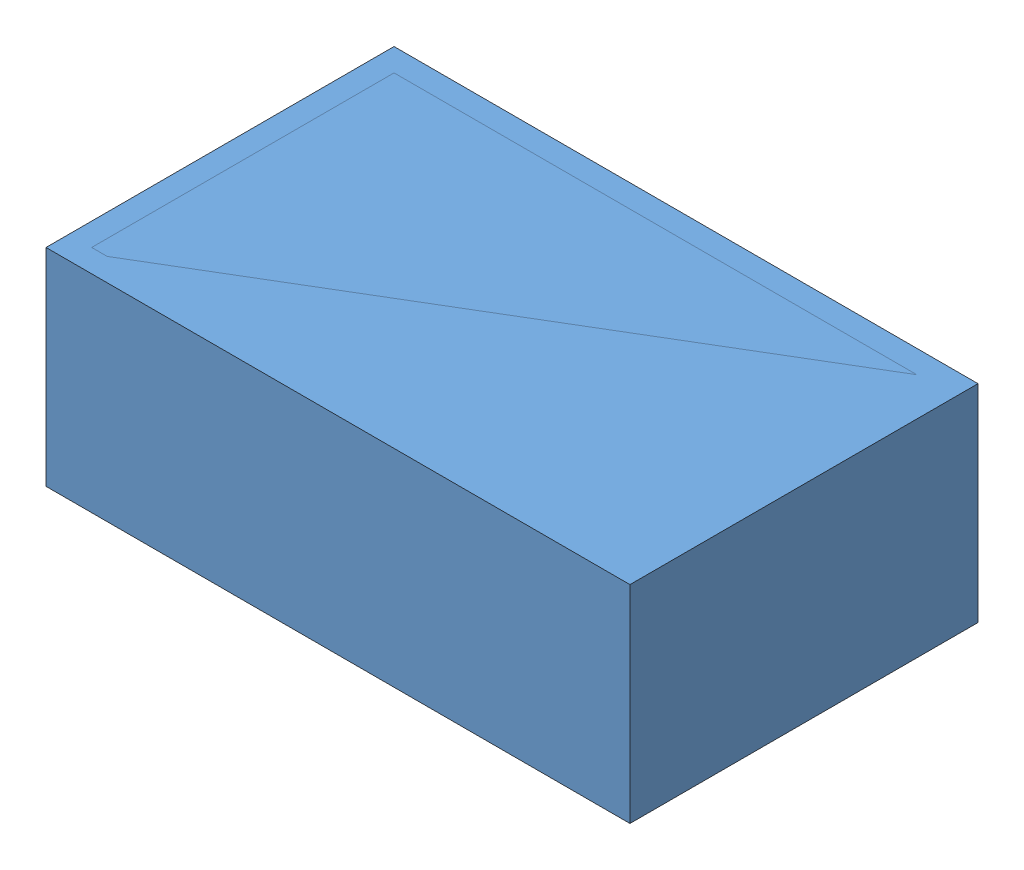
SolidWorks assembly Коробка 90х150х53 в сборе, configuration По умолчанию. Lengths in mm.
Overall size (153.02 53.98 92.02).
2 component instances, 2 part files, 4 mates.
Components (placement in the parent):
- Коробка 90х150х53 коробка-1: Коробка 90х150х53 коробка [По умолчанию] at origin size (151 53.5 90)
- Коробка 90х150х53 дно-1: Коробка 90х150х53 дно [По умолчанию] at (0 2.0374 0) x (1 0 0) z (0 1 0) size (153.02 92.02 4.01)
Mates (geometry in assembly coordinates):
- На месте1: in place: plane of Коробка 90х150х53 коробка-1 through (0 2.0374 0) normal (0 1 0); plane of Коробка 90х150х53 дно-1 through (0 2.0374 0) normal (0 1 0); moOrthogonalPlaneRef_w of Коробка 90х150х53 коробка-1 through (0 2.0374 0) normal (0 1 0); plane of Коробка 90х150х53 дно-1 through (0 2.0374 0) normal (0 0 -1); plane of Коробка 90х150х53 коробка-1 through (0 2.0374 0) normal (0 1 0); plane of Коробка 90х150х53 дно-1 through (0 2.0374 0) normal (1 0 0); plane of Коробка 90х150х53 коробка-1 through (0 2.0374 0) normal (0 1 0); unknown of Коробка 90х150х53 дно-1
- Совпадение1: coincident: plane of Коробка 90х150х53 коробка-1; plane of Коробка 90х150х53 дно-1
- Совпадение2: coincident: moOrthogonalPlaneRef_w of Коробка 90х150х53 коробка-1; plane of Коробка 90х150х53 дно-1 through (0 2.0374 0) normal (0 0 -1)
- Совпадение3: coincident: moOrthogonalPlaneRef_w of Коробка 90х150х53 коробка-1; plane of Коробка 90х150х53 дно-1 through (0 2.0374 0) normal (1 0 0)
